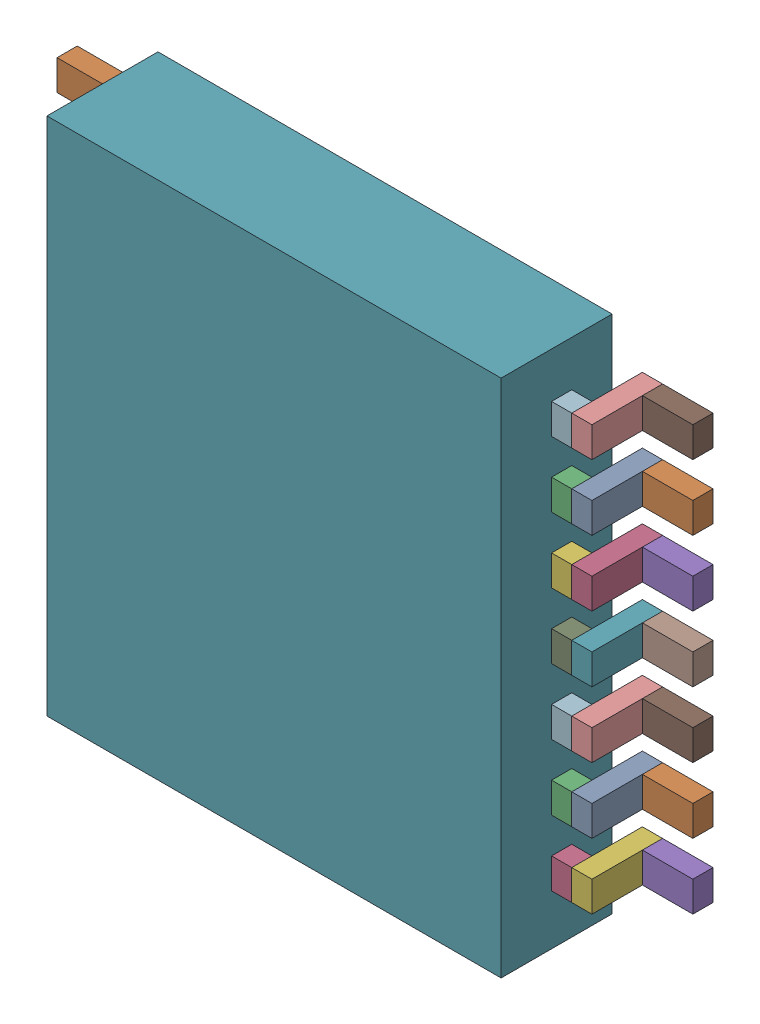
SolidWorks assembly U29, configuration Default. Lengths in mm.
Overall size (6.3 5.15 1.2).
86 component instances, 4 part files, 0 mates.
Components (placement in the parent):
- 836750064-1: 836750064 [Default] at (122.25 75.95 0) size (0.2 0.3 0.7)
  - Extruded_24-1: Extruded_24 [Default] at origin size (0.2 0.3 0.7)
- 836751344-1: 836751344 [Default] at (121.9 75.95 0) size (0.5 0.3 0.2)
  - Extruded_25-1: Extruded_25 [Default] at origin size (0.5 0.3 0.2)
- 836749808-1: 836749808 [Default] at (122.45 75.95 0.5) size (0.2 0.3 0.2)
  - Extruded_26-1: Extruded_26 [Default] at origin size (0.2 0.3 0.2)
- 836750064-2: 836750064 [Default] at (122.25 75.3 0) size (0.2 0.3 0.7)
  - Extruded_24-1: Extruded_24 [Default] at origin size (0.2 0.3 0.7)
- 836751344-2: 836751344 [Default] at (121.9 75.3 0) size (0.5 0.3 0.2)
  - Extruded_25-1: Extruded_25 [Default] at origin size (0.5 0.3 0.2)
- 836749808-2: 836749808 [Default] at (122.45 75.3 0.5) size (0.2 0.3 0.2)
  - Extruded_26-1: Extruded_26 [Default] at origin size (0.2 0.3 0.2)
- 836750064-3: 836750064 [Default] at (122.25 74.65 0) size (0.2 0.3 0.7)
  - Extruded_24-1: Extruded_24 [Default] at origin size (0.2 0.3 0.7)
- 836751344-3: 836751344 [Default] at (121.9 74.65 0) size (0.5 0.3 0.2)
  - Extruded_25-1: Extruded_25 [Default] at origin size (0.5 0.3 0.2)
- 836749808-3: 836749808 [Default] at (122.45 74.65 0.5) size (0.2 0.3 0.2)
  - Extruded_26-1: Extruded_26 [Default] at origin size (0.2 0.3 0.2)
- 836750064-4: 836750064 [Default] at (122.2546 74 0) size (0.2 0.3 0.7)
  - Extruded_24-1: Extruded_24 [Default] at origin size (0.2 0.3 0.7)
- 836751344-4: 836751344 [Default] at (121.9046 74 0) size (0.5 0.3 0.2)
  - Extruded_25-1: Extruded_25 [Default] at origin size (0.5 0.3 0.2)
- 836749808-4: 836749808 [Default] at (122.4546 74 0.5) size (0.2 0.3 0.2)
  - Extruded_26-1: Extruded_26 [Default] at origin size (0.2 0.3 0.2)
- 836750064-5: 836750064 [Default] at (122.2546 73.35 0) size (0.2 0.3 0.7)
  - Extruded_24-1: Extruded_24 [Default] at origin size (0.2 0.3 0.7)
- 836751344-5: 836751344 [Default] at (121.9046 73.35 0) size (0.5 0.3 0.2)
  - Extruded_25-1: Extruded_25 [Default] at origin size (0.5 0.3 0.2)
- 836749808-5: 836749808 [Default] at (122.4546 73.35 0.5) size (0.2 0.3 0.2)
  - Extruded_26-1: Extruded_26 [Default] at origin size (0.2 0.3 0.2)
- 836750064-6: 836750064 [Default] at (122.2546 72.7 0) size (0.2 0.3 0.7)
  - Extruded_24-1: Extruded_24 [Default] at origin size (0.2 0.3 0.7)
- 836751344-6: 836751344 [Default] at (121.9046 72.7 0) size (0.5 0.3 0.2)
  - Extruded_25-1: Extruded_25 [Default] at origin size (0.5 0.3 0.2)
- 836749808-6: 836749808 [Default] at (122.4546 72.7 0.5) size (0.2 0.3 0.2)
  - Extruded_26-1: Extruded_26 [Default] at origin size (0.2 0.3 0.2)
- 836750064-7: 836750064 [Default] at (122.25 72.05 0) size (0.2 0.3 0.7)
  - Extruded_24-1: Extruded_24 [Default] at origin size (0.2 0.3 0.7)
- 836751344-7: 836751344 [Default] at (121.9 72.05 0) size (0.5 0.3 0.2)
  - Extruded_25-1: Extruded_25 [Default] at origin size (0.5 0.3 0.2)
- 836749808-7: 836749808 [Default] at (122.45 72.05 0.5) size (0.2 0.3 0.2)
  - Extruded_26-1: Extruded_26 [Default] at origin size (0.2 0.3 0.2)
- 836750064-8: 836750064 [Default] at (127.35 75.95 0) size (0.2 0.3 0.7)
  - Extruded_24-1: Extruded_24 [Default] at origin size (0.2 0.3 0.7)
- 836751344-8: 836751344 [Default] at (127.7 75.95 0) size (0.5 0.3 0.2)
  - Extruded_25-1: Extruded_25 [Default] at origin size (0.5 0.3 0.2)
- 836749808-8: 836749808 [Default] at (127.15 75.95 0.5) size (0.2 0.3 0.2)
  - Extruded_26-1: Extruded_26 [Default] at origin size (0.2 0.3 0.2)
- 836750064-9: 836750064 [Default] at (127.35 75.3 0) size (0.2 0.3 0.7)
  - Extruded_24-1: Extruded_24 [Default] at origin size (0.2 0.3 0.7)
- 836751344-9: 836751344 [Default] at (127.7 75.3 0) size (0.5 0.3 0.2)
  - Extruded_25-1: Extruded_25 [Default] at origin size (0.5 0.3 0.2)
- 836749808-9: 836749808 [Default] at (127.15 75.3 0.5) size (0.2 0.3 0.2)
  - Extruded_26-1: Extruded_26 [Default] at origin size (0.2 0.3 0.2)
- 836750064-10: 836750064 [Default] at (127.35 74.65 0) size (0.2 0.3 0.7)
  - Extruded_24-1: Extruded_24 [Default] at origin size (0.2 0.3 0.7)
- 836751344-10: 836751344 [Default] at (127.7 74.65 0) size (0.5 0.3 0.2)
  - Extruded_25-1: Extruded_25 [Default] at origin size (0.5 0.3 0.2)
- 836749808-10: 836749808 [Default] at (127.15 74.65 0.5) size (0.2 0.3 0.2)
  - Extruded_26-1: Extruded_26 [Default] at origin size (0.2 0.3 0.2)
- 836750064-11: 836750064 [Default] at (127.35 74 0) size (0.2 0.3 0.7)
  - Extruded_24-1: Extruded_24 [Default] at origin size (0.2 0.3 0.7)
- 836751344-11: 836751344 [Default] at (127.7 74 0) size (0.5 0.3 0.2)
  - Extruded_25-1: Extruded_25 [Default] at origin size (0.5 0.3 0.2)
- 836749808-11: 836749808 [Default] at (127.15 74 0.5) size (0.2 0.3 0.2)
  - Extruded_26-1: Extruded_26 [Default] at origin size (0.2 0.3 0.2)
- 836750064-12: 836750064 [Default] at (127.35 73.35 0) size (0.2 0.3 0.7)
  - Extruded_24-1: Extruded_24 [Default] at origin size (0.2 0.3 0.7)
- 836751344-12: 836751344 [Default] at (127.7 73.35 0) size (0.5 0.3 0.2)
  - Extruded_25-1: Extruded_25 [Default] at origin size (0.5 0.3 0.2)
- 836749808-12: 836749808 [Default] at (127.15 73.35 0.5) size (0.2 0.3 0.2)
  - Extruded_26-1: Extruded_26 [Default] at origin size (0.2 0.3 0.2)
- 836750064-13: 836750064 [Default] at (127.35 72.7 0) size (0.2 0.3 0.7)
  - Extruded_24-1: Extruded_24 [Default] at origin size (0.2 0.3 0.7)
- 836751344-13: 836751344 [Default] at (127.7 72.7 0) size (0.5 0.3 0.2)
  - Extruded_25-1: Extruded_25 [Default] at origin size (0.5 0.3 0.2)
- 836749808-13: 836749808 [Default] at (127.15 72.7 0.5) size (0.2 0.3 0.2)
  - Extruded_26-1: Extruded_26 [Default] at origin size (0.2 0.3 0.2)
- 836749808-14: 836749808 [Default] at (127.15 72.05 0.5) size (0.2 0.3 0.2)
  - Extruded_26-1: Extruded_26 [Default] at origin size (0.2 0.3 0.2)
- 836751344-14: 836751344 [Default] at (127.7 72.05 0) size (0.5 0.3 0.2)
  - Extruded_25-1: Extruded_25 [Default] at origin size (0.5 0.3 0.2)
- 836750064-14: 836750064 [Default] at (127.35 72.05 0) size (0.2 0.3 0.7)
  - Extruded_24-1: Extruded_24 [Default] at origin size (0.2 0.3 0.7)
- 810381200-1: 810381200 [Default] at (124.8 73.975 0.1) size (4.5 5.15 1.1)
  - Extruded_44-1: Extruded_44 [Default] at origin size (4.5 5.15 1.1)
